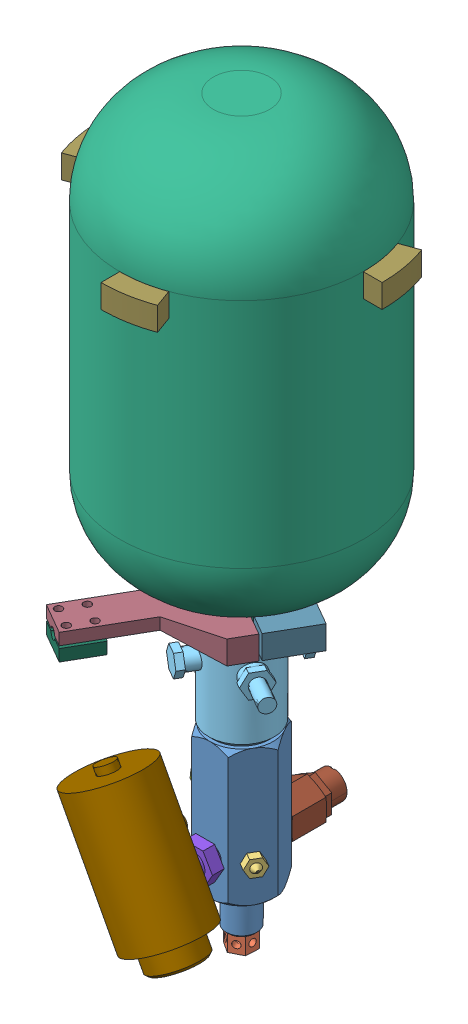
SolidWorks assembly SubSys_OxPress, configuration Standard. Lengths in mm.
Overall size (143.95 315 143.95).
18 component instances, 15 part files, 34 mates.
Components (placement in the parent):
- P17_Ox_Press_Manifold-1: P17_Ox_Press_Manifold [Default] at (0 -41.5898 0) size (34.29 75 27)
- P78_Diffusor-1: P78_Diffusor [Standard] at (0 -31.5898 0) x (-0.837169 0 -0.546944) z (-0.546944 0 0.837169) size (11.55 17 10)
- P9_Bleed_Orifice-1: P9_Bleed_Orifice [Default] at (11.6913 -8.5898 6.75) x (0.5 0 -0.866025) z (0.866025 0 0.5) size (8.08 7 13)
- P18_Ox_Press_Check_Valve-1: P18_Ox_Press_Check_Valve [Standard] at (0 15.0102 0) x (0 -1 0) z (0 0 1) size (16.8 13.16 13.16)
- P3_Press_Reg-1: P3_Press_Reg [Standard] at (0 290.4102 0) x (-0.866025 0 -0.5) z (-0.5 0 0.866025) size (58.5 79.6 44)
- P16_Ox_Press_Tank-1: P16_Ox_Press_Tank [Standard] at (0 266.4102 0) x (-0.837169 0 -0.546944) z (-0.546944 0 0.837169) size (104 196.54 104)
- P8_Pressure_Sensor-1: P8_Pressure_Sensor [Default] at (-11.6913 -8.5898 -6.75) x (-0.866025 0 -0.5) z (0.09665 0.98114 -0.167404) size (35.2 13.2 14.52)
- P20_R-1-8_Double_Nipple-1: P20_R-1-8_Double_Nipple [Default] at (0 -8.5898 20.5) x (1 0 0) z (0 1 0) size (16.17 21 14)
- P21_Solenoid_Vent_Valve-1: P21_Solenoid_Vent_Valve [Default] at (11.7368 -30.6635 38.5) x (-0.469472 0.882948 0) z (0 0 -1) size (67 33 35)
- P10_G_1-4_USIT_FKM-1: P10_G_1-4_USIT_FKM [Default] at (0 -26.5898 0) size (20.6 2 20.6)
- P6_Safety_Valve-1: P6_Safety_Valve [Default] at (0 -8.5898 -28.5) size (16.08 18.56 34)
- P79_Spacer_OxPressTank-1: P79_Spacer_OxPressTank [Standard] at (0 216.4102 0) size (20.52 10 11.14)
- P79_Spacer_OxPressTank-2: P79_Spacer_OxPressTank [Standard] at (0 216.4102 0) x (0 0 -1) z (1 0 0) size (20.52 10 11.14)
- P79_Spacer_OxPressTank-3: P79_Spacer_OxPressTank [Standard] at (0 216.4102 0) x (-1 0 0) z (0 0 -1) size (20.52 10 11.14)
- P79_Spacer_OxPressTank-4: P79_Spacer_OxPressTank [Standard] at (0 216.4102 0) x (0 0 1) z (-1 0 0) size (20.52 10 11.14)
- P24_Ox_Vent_Tube_Holder-1: P24_Ox_Vent_Tube_Holder [Standard] at (-0.5 82.9579 0.866) x (0.866025 0 0.5) z (0.5 0 -0.866025) size (47.93 10 58)
- P25_Ox_Vent_Tube_Holder_Bracket_Large-2: P25_Ox_Vent_Tube_Holder_Bracket_Large [Standard] at (0.5 72.9579 -0.866) x (0.866025 0 0.5) z (-0.5 0 0.866025) size (48 10 20)
- P26_Ox_Vent_Tube_Holder_Bracket_Small-1: P26_Ox_Vent_Tube_Holder_Bracket_Small [Standard] at (-25.75 71.9579 44.6003) x (0.866025 0 0.5) z (-0.5 0 0.866025) size (15 5 15)
Mates (geometry in assembly coordinates):
- Konzentrisch1: concentric: cylinder of P17_Ox_Press_Manifold-1 through (0 14.4102 0) axis (0 1 0) radius 9.5
- Konzentrisch2: concentric anti-aligned: cylinder of P17_Ox_Press_Manifold-1 through (0 -26.5898 0) axis (0 -1 0) radius 6.58; cylinder of Diffusor_6kant-1 through (0 -41.5898 0) axis (0 1 0) radius 3.935
- Deckungsgleich2: coincident anti-aligned: plane of P17_Ox_Press_Manifold-1 through (0 -41.5898 0) normal (0 -1 0); plane of Diffusor_6kant-1 through (0 -41.5898 0) normal (0 1 0)
- Konzentrisch3: concentric aligned: cylinder of P17_Ox_Press_Manifold-1 through (17.537 -8.5898 10.125) axis (-0.866025 0 -0.5) radius 2.5; cylinder of P9_Bleed_Orifice-1 through (11.6913 -8.5898 6.75) axis (-0.866025 0 -0.5) radius 2.942
- Deckungsgleich3: coincident anti-aligned: plane of P17_Ox_Press_Manifold-1 through (7.7942 33.4102 13.5) normal (0.866025 0 0.5); plane of P9_Bleed_Orifice-1 through (11.6913 -8.5898 6.75) normal (-0.866025 0 -0.5)
- Konzentrisch4: concentric anti-aligned: cylinder of P17_Ox_Press_Manifold-1 through (0 14.4102 0) axis (0 1 0) radius 9.5; cylinder of P18_Ox_Press_Check_Valve-1 through (0 6.8602 0) axis (0 -1 0) radius 6.58
- Abstand1: distance = 1.5 mm anti-aligned: plane of P17_Ox_Press_Manifold-1 through (0 -2.5898 0) normal (0 1 0); plane of P18_Ox_Press_Check_Valve-1 through (2.825 -1.0898 0) normal (0 -1 0)
- Konzentrisch5: concentric aligned: cylinder of P17_Ox_Press_Manifold-1 through (0 14.4102 0) axis (0 1 0) radius 9.5; cylinder of P3_Press_Reg-1 through (0 33.4102 0) axis (0 1 0) radius 14
- Parallel1: parallel aligned: plane of P17_Ox_Press_Manifold-1 through (-7.7942 33.4102 -13.5) normal (-0.866025 0 -0.5); plane of P3_Press_Reg-1 through (-24.6817 60.4102 -14.25) normal (-0.866025 0 -0.5)
- Deckungsgleich7: coincident anti-aligned: plane of P17_Ox_Press_Manifold-1 through (0 33.4102 0) normal (0 1 0); plane of P3_Press_Reg-1 through (0 33.4102 0) normal (0 -1 0)
- Konzentrisch6: concentric aligned: cylinder of P3_Press_Reg-1 through (0 33.4102 0) axis (0 1 0) radius 14; cylinder of P16_Ox_Press_Tank-1 through (0 266.4102 0) axis (0 1 0) radius 52
- Deckungsgleich8: coincident anti-aligned: plane of P3_Press_Reg-1 through (0 70.4102 0) normal (0 1 0); plane of P16_Ox_Press_Tank-1 through (-11.7204 70.4102 -7.6572) normal (0 -1 0)
- Konzentrisch7: concentric anti-aligned: cylinder of P17_Ox_Press_Manifold-1 through (17.537 -8.5898 10.125) axis (-0.866025 0 -0.5) radius 2.5; cylinder of P8_Pressure_Sensor-1 through (10.9868 -8.5898 6.3432) axis (0.866025 0 0.5) radius 3
- Deckungsgleich9: coincident anti-aligned: plane of P17_Ox_Press_Manifold-1 through (-7.7942 33.4102 -13.5) normal (-0.866025 0 -0.5); plane of P8_Pressure_Sensor-1 through (-12.3292 -15.0654 -5.6451) normal (0.866025 0 0.5)
- Konzentrisch8: concentric aligned: cylinder of P17_Ox_Press_Manifold-1 through (0 -8.5898 -13.5) axis (0 0 1) radius 4.4; cylinder of P20_R-1-8_Double_Nipple-1 through (0 -8.5898 7.5) axis (0 0 1) radius 4.85
- Abstand2: distance = 2 mm anti-aligned: plane of P17_Ox_Press_Manifold-1 through (-7.7942 33.4102 13.5) normal (0 0 1); plane of P20_R-1-8_Double_Nipple-1 through (0 -8.5898 15.5) normal (0 0 -1)
- Konzentrisch9: concentric aligned: cylinder of P20_R-1-8_Double_Nipple-1 through (0 -8.5898 28.5) axis (0 0 -1) radius 4.85; cylinder of P21_Solenoid_Vent_Valve-1 through (0 -8.5898 31) axis (0 0 -1) radius 4.85
- Abstand3: distance = 18 mm: plane of P20_R-1-8_Double_Nipple-1 through (0 -8.5898 20.5) normal (0 0 1); cylinder of P21_Solenoid_Vent_Valve-1 through (11.7368 -30.6635 38.5) axis (0.469472 -0.882948 0) radius 16.5
- Winkel2: planar angle = 2.6529 rad anti-aligned: plane of P21_Solenoid_Vent_Valve-1 through (7.5115 -22.717 49.5) normal (0.469472 -0.882948 0); plane of P17_Ox_Press_Manifold-1 through (0 -24.5898 0) normal (0 -1 0)
- Deckungsgleich13: coincident anti-aligned: plane of P17_Ox_Press_Manifold-1 through (0 -24.5898 0) normal (0 -1 0); plane of P10_G_1-4_USIT_FKM-1 through (0 -24.5898 0) normal (0 1 0)
- Konzentrisch10: concentric aligned: cylinder of P17_Ox_Press_Manifold-1 through (0 -26.5898 0) axis (0 -1 0) radius 6.58; cylinder of P10_G_1-4_USIT_FKM-1 through (0 -24.5898 0) axis (0 -1 0) radius 7
- Konzentrisch11: concentric aligned: cylinder of P17_Ox_Press_Manifold-1 through (0 -8.5898 -13.5) axis (0 0 1) radius 4.4; cylinder of P6_Safety_Valve-1 through (0 -8.5898 -6.84) axis (0 0 1) radius 5
- Deckungsgleich14: coincident anti-aligned: plane of P17_Ox_Press_Manifold-1 through (7.7942 33.4102 -13.5) normal (0 0 -1); plane of P6_Safety_Valve-1 through (8.8104 0.3244 -13.5) normal (0 0 1)
- Konzentrisch12: concentric anti-aligned: cylinder of P16_Ox_Press_Tank-1 through (0 266.4102 0) axis (0 1 0) radius 52; cylinder of Spacer_OxPressTank-1 through (0 226.4102 0) axis (0 -1 0) radius 52
- Deckungsgleich15: coincident anti-aligned: circle of P16_Ox_Press_Tank-1; plane of Spacer_OxPressTank-1 through (0 226.4102 0) normal (0 1 0)
- Konzentrisch13: concentric aligned: cylinder of P16_Ox_Press_Tank-1 through (0 266.4102 0) axis (0 1 0) radius 14; cylinder of P24_Ox_Vent_Tube_Holder-1 through (0 72.9579 0) axis (0 1 0) radius 14
- Parallel2: parallel aligned: plane of P3_Press_Reg-1 through (-11 290.4102 19.0526) normal (-0.5 0 0.866025); plane of P24_Ox_Vent_Tube_Holder-1 through (-35.9952 72.9579 47.3455) normal (-0.5 0 0.866025)
- Deckungsgleich17: coincident anti-aligned: circle of P16_Ox_Press_Tank-1; plane of P24_Ox_Vent_Tube_Holder-1 through (0 82.9579 0) normal (0 1 0)
- Konzentrisch17: concentric anti-aligned: cylinder of P16_Ox_Press_Tank-1 through (0 266.4102 0) axis (0 1 0) radius 14; cylinder of P25_Ox_Vent_Tube_Holder_Bracket_Large-2 through (0 82.9579 0) axis (0 -1 0) radius 14
- Parallel5: parallel aligned: plane of P24_Ox_Vent_Tube_Holder-1 through (20.2536 72.9579 12.8481) normal (0.866025 0 0.5); plane of P25_Ox_Vent_Tube_Holder_Bracket_Large-2 through (20.7846 82.9579 12) normal (0.866025 0 0.5)
- Deckungsgleich20: coincident aligned: plane of P24_Ox_Vent_Tube_Holder-1 through (0 82.9579 0) normal (0 1 0); plane of P25_Ox_Vent_Tube_Holder_Bracket_Large-2 through (0 82.9579 0) normal (0 1 0)
- Konzentrisch18: concentric anti-aligned: cylinder of P24_Ox_Vent_Tube_Holder-1 through (-31.8971 72.9579 46.2474) axis (0 1 0) radius 1.6; cylinder of P26_Ox_Vent_Tube_Holder_Bracket_Small-1 through (-31.8971 76.9579 46.2474) axis (0 -1 0) radius 1.6
- Konzentrisch19: concentric anti-aligned: cylinder of P24_Ox_Vent_Tube_Holder-1 through (-24.1029 72.9579 50.7474) axis (0 1 0) radius 1.6; cylinder of P26_Ox_Vent_Tube_Holder_Bracket_Small-1 through (-24.1029 76.9579 50.7474) axis (0 -1 0) radius 1.6
- Konzentrisch20: concentric aligned: cylinder of P24_Ox_Vent_Tube_Holder-1 through (-13.7321 77.4579 23.7847) axis (-0.5 0 0.866025) radius 2.25; cylinder of P26_Ox_Vent_Tube_Holder_Bracket_Small-1 through (-22 77.4579 38.1051) axis (-0.5 0 0.866025) radius 2.25
